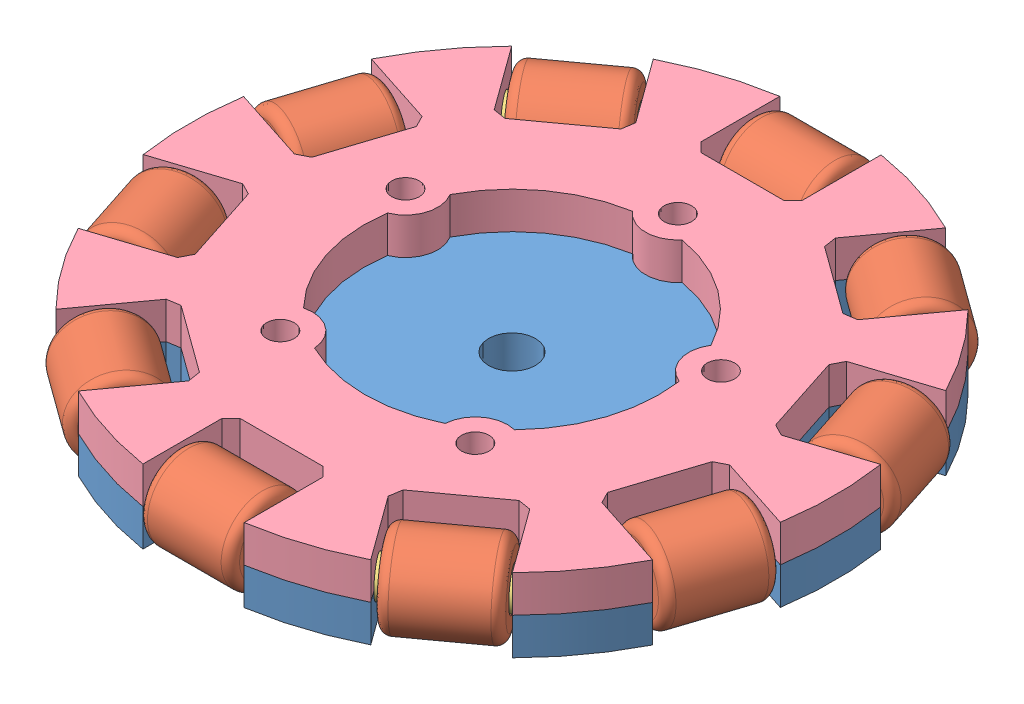
SolidWorks assembly omniwheel-baugruppe, configuration Standard. Lengths in mm.
Overall size (72.86 16.34 72.97).
22 component instances, 4 part files, 42 mates.
Components (placement in the parent):
- omniwheel-1: omniwheel [Standard] at origin size (70 10 69.13)
- omniwheel-wheel-1: omniwheel-wheel [Standard] at (-5 4 -31.0652) x (0 0 -1) z (1 0 0) size (9 9 10)
- omniwheel-wheel-holder-1: omniwheel-wheel-holder [Standard] at (-7 4 -31.0652) x (0 0 -1) z (1 0 0) size (3.92 3.92 14)
- omniwheel-wheel-2: omniwheel-wheel [Standard] at (-22.3047 4 -22.1933) x (-0.584585 0.104205 -0.804613) z (0.809017 0 -0.587785) size (9 9 10)
- omniwheel-wheel-holder-2: omniwheel-wheel-holder [Standard] at (-23.9228 4 -21.0177) x (-0.584585 0.104205 -0.804613) z (0.809017 0 -0.587785) size (3.92 3.92 14)
- omniwheel-wheel-5: omniwheel-wheel [Standard] at (-31.0898 4 -4.8444) x (-0.948815 0.068621 -0.308289) z (0.309017 0 -0.951057) size (9 9 10)
- omniwheel-wheel-holder-5: omniwheel-wheel-holder [Standard] at (-31.7078 4 -2.9423) x (-0.948815 0.068621 -0.308289) z (0.309017 0 -0.951057) size (3.92 3.92 14)
- omniwheel-wheel-7: omniwheel-wheel [Standard] at (-27.9996 4 14.3549) x (-0.946378 -0.099063 0.307497) z (-0.309017 0 -0.951057) size (9 9 10)
- omniwheel-wheel-holder-7: omniwheel-wheel-holder [Standard] at (-27.3816 4 16.2571) x (-0.946378 -0.099063 0.307497) z (-0.309017 0 -0.951057) size (3.92 3.92 14)
- omniwheel-wheel-9: omniwheel-wheel [Standard] at (-14.2146 4 28.0712) x (-0.548186 -0.360833 0.754514) z (-0.809017 0 -0.587785) size (9 9 10)
- omniwheel-wheel-holder-9: omniwheel-wheel-holder [Standard] at (-12.5965 4 29.2467) x (-0.548186 -0.360833 0.754514) z (-0.809017 0 -0.587785) size (3.92 3.92 14)
- omniwheel-wheel-11: omniwheel-wheel [Standard] at (5 4 31.0652) x (0 -0.642788 0.766044) z (-1 0 0) size (9 9 10)
- omniwheel-wheel-holder-11: omniwheel-wheel-holder [Standard] at (7 4 31.0652) x (0 -0.642788 0.766044) z (-1 0 0) size (3.92 3.92 14)
- omniwheel-wheel-13: omniwheel-wheel [Standard] at (22.3047 4 22.1933) x (0.262972 -0.894337 0.361949) z (-0.809017 0 0.587785) size (9 9 10)
- omniwheel-wheel-holder-13: omniwheel-wheel-holder [Standard] at (23.9228 4 21.0177) x (0.262972 -0.894337 0.361949) z (-0.809017 0 0.587785) size (3.92 3.92 14)
- omniwheel-wheel-15: omniwheel-wheel [Standard] at (31.0898 4 4.8444) x (-0.457531 -0.876679 -0.148661) z (-0.309017 0 0.951057) size (9 9 10)
- omniwheel-wheel-holder-15: omniwheel-wheel-holder [Standard] at (31.7078 4 2.9423) x (-0.457531 -0.876679 -0.148661) z (-0.309017 0 0.951057) size (3.92 3.92 14)
- omniwheel-wheel-17: omniwheel-wheel [Standard] at (27.9996 4 -14.3549) x (0.575041 0.796504 -0.186842) z (0.309017 0 0.951057) size (9 9 10)
- omniwheel-wheel-holder-17: omniwheel-wheel-holder [Standard] at (27.3816 4 -16.2571) x (0.575041 0.796504 -0.186842) z (0.309017 0 0.951057) size (3.92 3.92 14)
- omniwheel-wheel-19: omniwheel-wheel [Standard] at (14.2146 4 -28.0712) x (0.587785 0 -0.809017) z (0.809017 0 0.587785) size (9 9 10)
- omniwheel-wheel-holder-19: omniwheel-wheel-holder [Standard] at (12.5965 4 -29.2467) x (0.587785 0 -0.809017) z (0.809017 0 0.587785) size (3.92 3.92 14)
- omniwheel-top-1: omniwheel-top [Standard] at (0 8 0) x (-1 0 0) z (0 0 1) size (70 4 69.13)
Mates (geometry in assembly coordinates):
- Konzentrisch1: concentric aligned: cylinder of omniwheel-1 through (-7 4 -31.0652) axis (-1 0 0) radius 2; cylinder of omniwheel-wheel-holder-1 through (7 4 -31.0652) axis (-1 0 0) radius 1.96
- Deckungsgleich1: coincident: line of omniwheel-1 through (-7 4 -33.0652) axis (0 0 1); plane of omniwheel-wheel-holder-1 through (-7 4 -31.0652) normal (-1 0 0)
- Konzentrisch2: concentric aligned: circle of omniwheel-wheel-1; circle of omniwheel-wheel-holder-1
- Abstand1: distance = 0.5 mm anti-aligned: plane of omniwheel-1 through (-5.5 0 -37) normal (1 0 0); plane of omniwheel-wheel-1 through (-5 4 -31.0652) normal (-1 0 0)
- Konzentrisch3: concentric aligned: circle of omniwheel-wheel-2; circle of omniwheel-wheel-holder-2
- Konzentrisch4: concentric aligned: cylinder of omniwheel-1 through (-23.9228 4 -21.0177) axis (-0.809017 0 0.587785) radius 2; cylinder of omniwheel-wheel-holder-2 through (-12.5965 4 -29.2467) axis (-0.809017 0 0.587785) radius 1.96
- Deckungsgleich3: coincident anti-aligned: plane of omniwheel-1 through (-23.9228 4 -21.0177) normal (0.809017 0 -0.587785); plane of omniwheel-wheel-holder-2 through (-23.9228 4 -21.0177) normal (-0.809017 0 0.587785)
- Abstand2: distance = 0.5 mm anti-aligned: plane of omniwheel-1 through (-26.1976 0 -26.7008) normal (0.809017 0 -0.587785); plane of omniwheel-wheel-2 through (-22.3047 4 -22.1933) normal (-0.809017 0 0.587785)
- Konzentrisch7: concentric aligned: circle of omniwheel-wheel-5; circle of omniwheel-wheel-holder-5
- Konzentrisch8: concentric aligned: circle of omniwheel-1; cylinder of omniwheel-wheel-holder-5 through (-27.3816 4 -16.2571) axis (-0.309017 0 0.951057) radius 1.96
- Deckungsgleich4: coincident anti-aligned: plane of omniwheel-1 through (-31.7078 4 -2.9423) normal (0.309017 0 -0.951057); plane of omniwheel-wheel-holder-5 through (-31.7078 4 -2.9423) normal (-0.309017 0 0.951057)
- Abstand3: distance = 0.5 mm anti-aligned: plane of omniwheel-1 through (-36.8887 0 -6.2028) normal (0.309017 0 -0.951057); plane of omniwheel-wheel-5 through (-31.0898 4 -4.8444) normal (-0.309017 0 0.951057)
- Konzentrisch10: concentric aligned: circle of omniwheel-wheel-7; circle of omniwheel-wheel-holder-7
- Konzentrisch11: concentric aligned: cylinder of omniwheel-1 through (-27.3816 4 16.2571) axis (0.309017 0 0.951057) radius 2; cylinder of omniwheel-wheel-holder-7 through (-31.7078 4 2.9423) axis (0.309017 0 0.951057) radius 1.96
- Deckungsgleich5: coincident anti-aligned: plane of omniwheel-1 through (-27.3816 4 16.2571) normal (-0.309017 0 -0.951057); plane of omniwheel-wheel-holder-7 through (-27.3816 4 16.2571) normal (0.309017 0 0.951057)
- Abstand4: distance = 0.5 mm anti-aligned: plane of omniwheel-1 through (-33.4895 0 16.6644) normal (-0.309017 0 -0.951057); plane of omniwheel-wheel-7 through (-27.9996 4 14.3549) normal (0.309017 0 0.951057)
- Konzentrisch13: concentric aligned: circle of omniwheel-wheel-9; circle of omniwheel-wheel-holder-9
- Konzentrisch14: concentric aligned: cylinder of omniwheel-1 through (-12.5965 4 29.2467) axis (0.809017 0 0.587785) radius 2; cylinder of omniwheel-wheel-holder-9 through (-23.9228 4 21.0177) axis (0.809017 0 0.587785) radius 1.96
- Deckungsgleich6: coincident anti-aligned: plane of omniwheel-1 through (-12.5965 4 29.2467) normal (-0.809017 0 -0.587785); plane of omniwheel-wheel-holder-9 through (-12.5965 4 29.2467) normal (0.809017 0 0.587785)
- Abstand5: distance = 0.5 mm anti-aligned: plane of omniwheel-1 through (-17.2985 0 33.1664) normal (-0.809017 0 -0.587785); plane of omniwheel-wheel-9 through (-14.2146 4 28.0712) normal (0.809017 0 0.587785)
- Konzentrisch16: concentric aligned: circle of omniwheel-wheel-11; circle of omniwheel-wheel-holder-11
- Konzentrisch17: concentric aligned: cylinder of omniwheel-1 through (7 4 31.0652) axis (1 0 0) radius 2; cylinder of omniwheel-wheel-holder-11 through (-7 4 31.0652) axis (1 0 0) radius 1.96
- Deckungsgleich7: coincident anti-aligned: plane of omniwheel-1 through (7 4 31.0652) normal (-1 0 0); plane of omniwheel-wheel-holder-11 through (7 4 31.0652) normal (1 0 0)
- Abstand6: distance = 0.5 mm anti-aligned: plane of omniwheel-1 through (5.5 0 37) normal (-1 0 0); plane of omniwheel-wheel-11 through (5 4 31.0652) normal (1 0 0)
- Konzentrisch19: concentric aligned: circle of omniwheel-wheel-13; circle of omniwheel-wheel-holder-13
- Konzentrisch20: concentric aligned: cylinder of omniwheel-1 through (23.9228 4 21.0177) axis (0.809017 0 -0.587785) radius 2; cylinder of omniwheel-wheel-holder-13 through (12.5965 4 29.2467) axis (0.809017 0 -0.587785) radius 1.96
- Deckungsgleich8: coincident anti-aligned: plane of omniwheel-1 through (23.9228 4 21.0177) normal (-0.809017 0 0.587785); plane of omniwheel-wheel-holder-13 through (23.9228 4 21.0177) normal (0.809017 0 -0.587785)
- Abstand7: distance = 0.5 mm anti-aligned: plane of omniwheel-1 through (26.1976 0 26.7008) normal (-0.809017 0 0.587785); plane of omniwheel-wheel-13 through (22.3047 4 22.1933) normal (0.809017 0 -0.587785)
- Konzentrisch22: concentric aligned: circle of omniwheel-wheel-15; circle of omniwheel-wheel-holder-15
- Konzentrisch23: concentric aligned: cylinder of omniwheel-1 through (31.7078 4 2.9423) axis (0.309017 0 -0.951057) radius 2; cylinder of omniwheel-wheel-holder-15 through (27.3816 4 16.2571) axis (0.309017 0 -0.951057) radius 1.96
- Deckungsgleich9: coincident anti-aligned: plane of omniwheel-1 through (31.7078 4 2.9423) normal (-0.309017 0 0.951057); plane of omniwheel-wheel-holder-15 through (31.7078 4 2.9423) normal (0.309017 0 -0.951057)
- Abstand8: distance = 0.5 mm anti-aligned: plane of omniwheel-1 through (36.8887 0 6.2028) normal (-0.309017 0 0.951057); plane of omniwheel-wheel-15 through (31.0898 4 4.8444) normal (0.309017 0 -0.951057)
- Konzentrisch25: concentric aligned: circle of omniwheel-wheel-17; circle of omniwheel-wheel-holder-17
- Konzentrisch26: concentric aligned: cylinder of omniwheel-1 through (27.3816 4 -16.2571) axis (-0.309017 0 -0.951057) radius 2; cylinder of omniwheel-wheel-holder-17 through (31.7078 4 -2.9423) axis (-0.309017 0 -0.951057) radius 1.96
- Deckungsgleich10: coincident anti-aligned: plane of omniwheel-1 through (27.3816 4 -16.2571) normal (0.309017 0 0.951057); plane of omniwheel-wheel-holder-17 through (27.3816 4 -16.2571) normal (-0.309017 0 -0.951057)
- Abstand9: distance = 0.5 mm anti-aligned: plane of omniwheel-1 through (33.4895 0 -16.6644) normal (0.309017 0 0.951057); plane of omniwheel-wheel-17 through (27.9996 4 -14.3549) normal (-0.309017 0 -0.951057)
- Konzentrisch28: concentric aligned: circle of omniwheel-wheel-19; circle of omniwheel-wheel-holder-19
- Konzentrisch29: concentric aligned: cylinder of omniwheel-1 through (12.5965 4 -29.2467) axis (-0.809017 0 -0.587785) radius 2; cylinder of omniwheel-wheel-holder-19 through (23.9228 4 -21.0177) axis (-0.809017 0 -0.587785) radius 1.96
- Deckungsgleich11: coincident anti-aligned: plane of omniwheel-1 through (12.5965 4 -29.2467) normal (0.809017 0 0.587785); plane of omniwheel-wheel-holder-19 through (12.5965 4 -29.2467) normal (-0.809017 0 -0.587785)
- Abstand10: distance = 0.5 mm anti-aligned: plane of omniwheel-1 through (17.2985 0 -33.1664) normal (0.809017 0 0.587785); plane of omniwheel-wheel-19 through (14.2146 4 -28.0712) normal (-0.809017 0 -0.587785)
- Deckungsgleich12: coincident anti-aligned: axis of omniwheel-1 through (4 0 4) axis (0 0 -1); axis of omniwheel-top-1 through (4 0 4) axis (0 0 1)
- Deckungsgleich13: coincident anti-aligned: circle of omniwheel-1; circle of omniwheel-top-1
